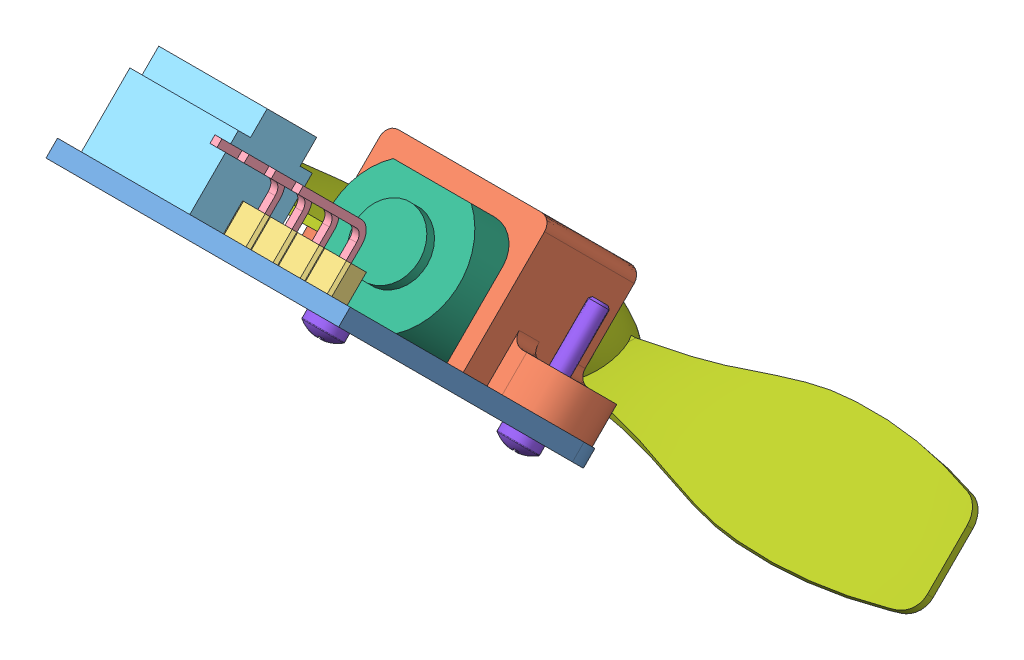
SolidWorks assembly STEP_MotorBoard, configuration Default. Lengths in mm.
Overall size (72.86 40.3 41.69).
12 component instances, 9 part files, 0 mates.
Components (placement in the parent):
- STEP_MotorBoard.stp-1: STEP_MotorBoard.stp [Default] at origin size (72.86 40.3 41.69)
  - 006_MotorControlBoard.stp-1: 006_MotorControlBoard.stp [Default] at (22.3357 6.1599 18.2056) x (1 0 0) z (0 0.707107 0.707107) size (27 1.5 35)
  - 007_MotorConnector.stp-1: 007_MotorConnector.stp [Default] at (14.9357 -11.3056 -1.3812) x (0 0.707107 0.707107) z (-1 0 0) size (11.7 11.6 26.6)
  - 008_MotorControlPinBase.stp-1: 008_MotorControlPinBase.stp [Default] at (19.8357 4.8164 14.7408) x (0 -0.707107 -0.707107) z (1 0 0) size (2.5 2.5 10)
  - 009_MotorControlPins.stp-1: 009_MotorControlPins.stp [Default] at (10.7607 7.6979 14.0867) x (0 0.707107 0.707107) z (-1 0 0) size (9.07 2.82 8.15)
  - 010_MotorControlChip.stp-1: 010_MotorControlChip.stp [Default] at (6.5857 -0.5576 9.3668) x (0 -0.707107 -0.707107) z (1 0 0) size (9.65 8.5 10)
  - 011_Motor.stp-1: 011_Motor.stp [Default] at (8.8378 -14.0633 -11.0686) x (-1 0 0) z (0 -0.707107 -0.707107) size (12 9.8 23.3)
  - 012_MotorPropeller.stp-1: 012_MotorPropeller.stp [Default] at (13.2378 -17.8774 -15.2964) size (72.86 11.99 11.99)
  - Screw GB_T 818 M1,6 x 10.stp-1: Screw GB_T 818 M1,6 x 10.stp [Default] at (-0.1643 -15.4068 -3.3611) x (0 0.707107 -0.707107) z (0.707107 0.5 0.5) size (11.28 3.2 3.2)
  - Screw GB_T 818 M1,6 x 10.stp-2: Screw GB_T 818 M1,6 x 10.stp [Default] at (17.8357 -15.4068 -3.3611) x (0 0.707107 -0.707107) z (0.707107 0.5 0.5) size (11.28 3.2 3.2)
  - ANSI B 18.2.4.1 M - M1,6 x 0,35Style 1.stp-1: ANSI B 18.2.4.1 M - M1,6 x 0,35Style 1.stp [Default] at (-0.1643 -15.1594 -3.6086) x (0 0.707107 -0.707107) z (0.707107 0.5 0.5) size (1.3 3.7 3.2)
  - ANSI B 18.2.4.1 M - M1,6 x 0,35Style 1.stp-2: ANSI B 18.2.4.1 M - M1,6 x 0,35Style 1.stp [Default] at (17.8357 -15.1594 -3.6086) x (0 0.707107 -0.707107) z (0.707107 0.5 0.5) size (1.3 3.7 3.2)
